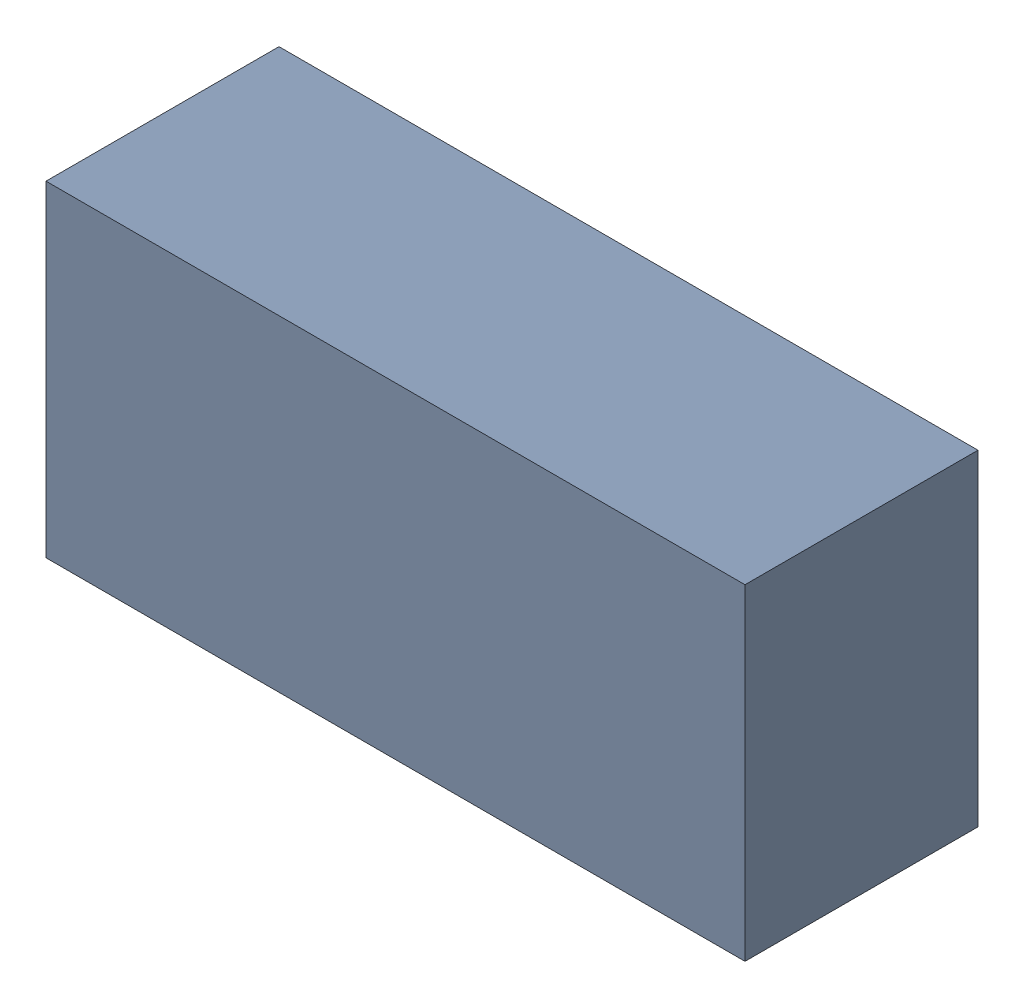
SolidWorks assembly Q1, configuration Default. Lengths in mm.
Overall size (3 1.4 1).
2 component instances, 1 part files, 0 mates.
Components (placement in the parent):
- 959206488-1: 959206488 [Default] at (75.057 92.3634 0.1) size (3 1.4 1)
  - Extruded-11-1: Extruded-11 [Default] at origin size (3 1.4 1)
